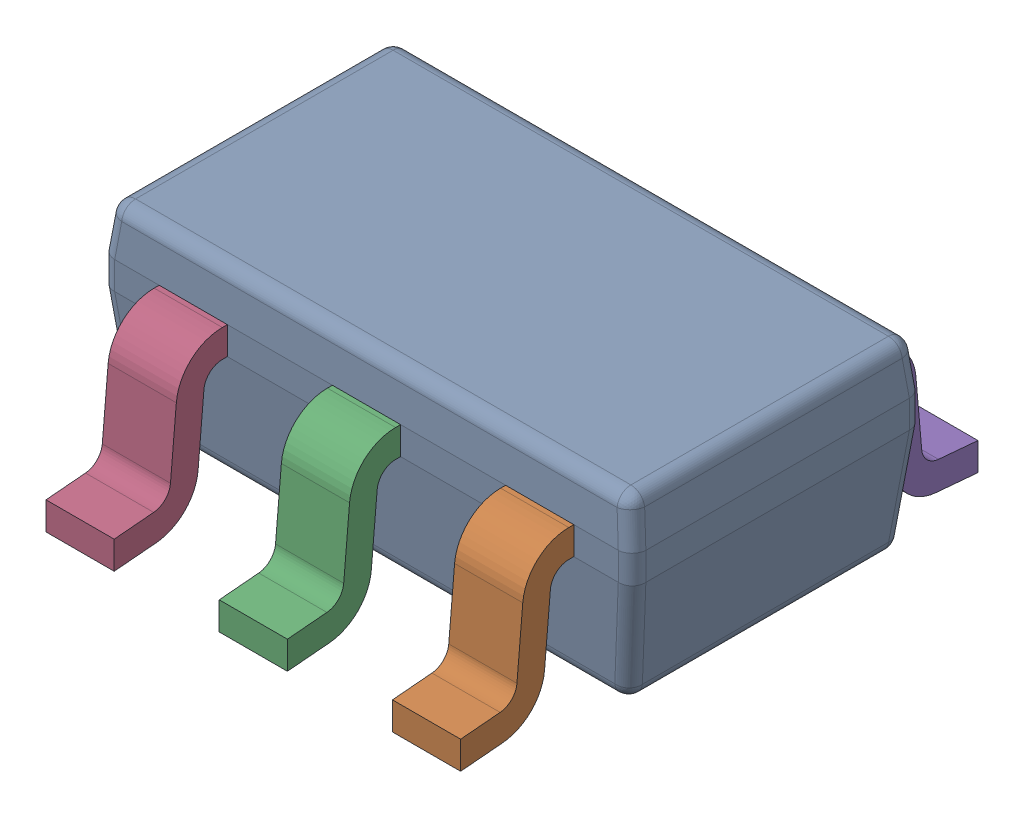
SolidWorks assembly sot-23-6.step, configuration Default. Lengths in mm.
Overall size (2.93 1.12 2.84).
7 component instances, 2 part files, 0 mates.
Components (placement in the parent):
- BODY_MF06A.step-1: BODY_MF06A.step [Default] at origin size (2.93 1.02 1.61)
- LEAD_MF06A.step-1: LEAD_MF06A.step [Default] at (0.9525 -0.6604 0.9652) size (0.37 0.86 0.62)
- LEAD_MF06A.step-2: LEAD_MF06A.step [Default] at (0 -0.6604 0.9652) size (0.37 0.86 0.62)
- LEAD_MF06A.step-3: LEAD_MF06A.step [Default] at (-0.9525 -0.6604 0.9652) size (0.37 0.86 0.62)
- LEAD_MF06A.step-4: LEAD_MF06A.step [Default] at (0.9525 -0.6604 -0.9652) x (-1 0 0) z (0 0 -1) size (0.37 0.86 0.62)
- LEAD_MF06A.step-5: LEAD_MF06A.step [Default] at (0 -0.6604 -0.9652) x (-1 0 0) z (0 0 -1) size (0.37 0.86 0.62)
- LEAD_MF06A.step-6: LEAD_MF06A.step [Default] at (-0.9525 -0.6604 -0.9652) x (-1 0 0) z (0 0 -1) size (0.37 0.86 0.62)
